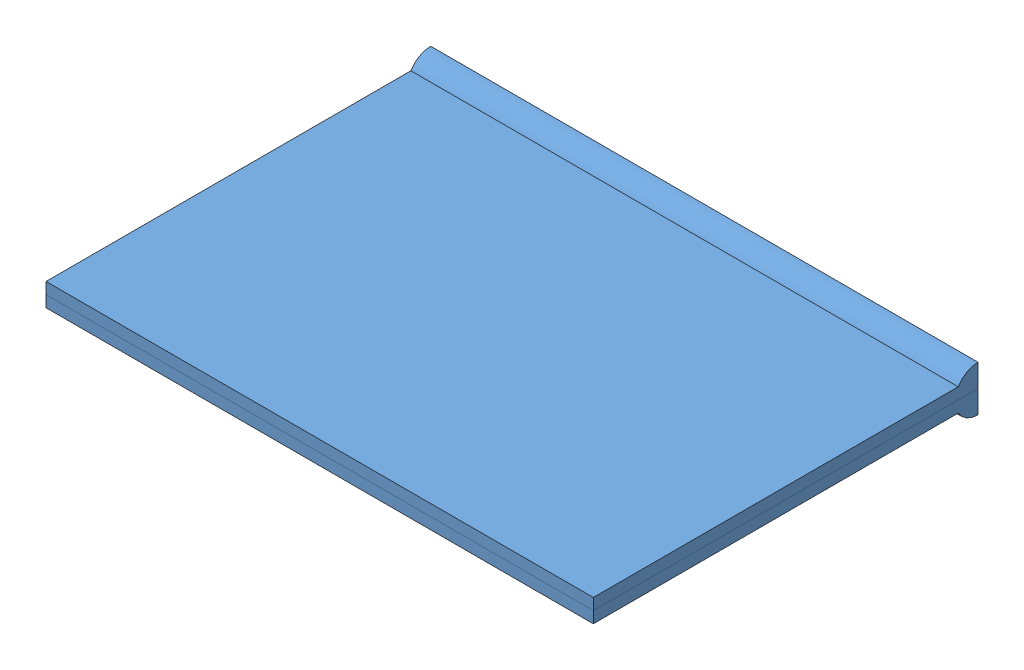
SolidWorks assembly Hinge assembly, configuration Default. Lengths in mm.
Overall size (19.05 1.59 13.39).
2 component instances, 1 part files, 7 mates.
Components (placement in the parent):
- Hinge-1: Hinge [Top] at (-19.0911 -0.3969 13.3874) size (19.05 0.79 13.39)
- Hinge-2: Hinge [Top] at (-0.0411 0.3969 13.3874) x (-1 0 0) z (0 0 1) size (19.05 0.79 13.39)
Mates (geometry in assembly coordinates):
- Coincident3: coincident aligned: plane of Hinge-1 through (-0.0411 0.3969 13.3874) normal (1 0 0); plane of Hinge-2 through (-0.0411 -0.3969 13.3874) normal (1 0 0)
- Coincident4: coincident: line of Hinge-2 through (19.05 -0.0411 0) axis (0 -1 0)
- Coincident5: coincident anti-aligned: line of Hinge-2 through (19.05 -0.0411 0) axis (0 -1 0); line of Hinge-1 through (0 19.05 -19.0911) axis (0 0 1)
- Coincident6: coincident aligned: plane of Hinge-1 through (-0.0411 0.3969 13.3874) normal (1 0 0); plane of Hinge-2 through (-0.0411 -0.3969 13.3874) normal (1 0 0)
- Parallel1: parallel anti-aligned: plane of Hinge-2 through (-0.0411 -0.3969 13.3874) normal (0 -1 0)
- Coincident8: coincident anti-aligned: plane of Hinge-2 through (-0.0411 0 0) normal (0 0 -1)
- Coincident9: coincident anti-aligned: plane of Hinge-1 through (-19.05 0 13.3874) normal (0 -1 0); plane of Hinge-2 through (0 0 13.3874) normal (0 1 0)
